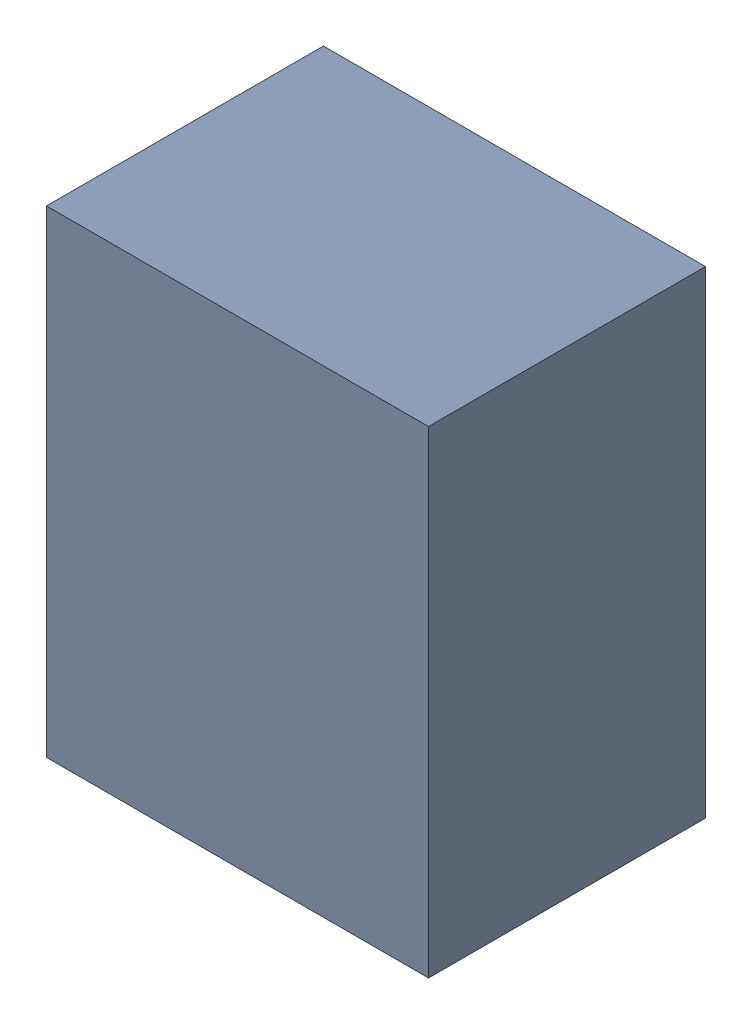
SolidWorks assembly U15, configuration Default. Lengths in mm.
Overall size (0.8 1 0.58).
2 component instances, 1 part files, 0 mates.
Components (placement in the parent):
- 836751984-1: 836751984 [Default] at (133.05 54 0.5) size (0.8 1 0.58)
  - Extruded_32-1: Extruded_32 [Default] at origin size (0.8 1 0.58)
